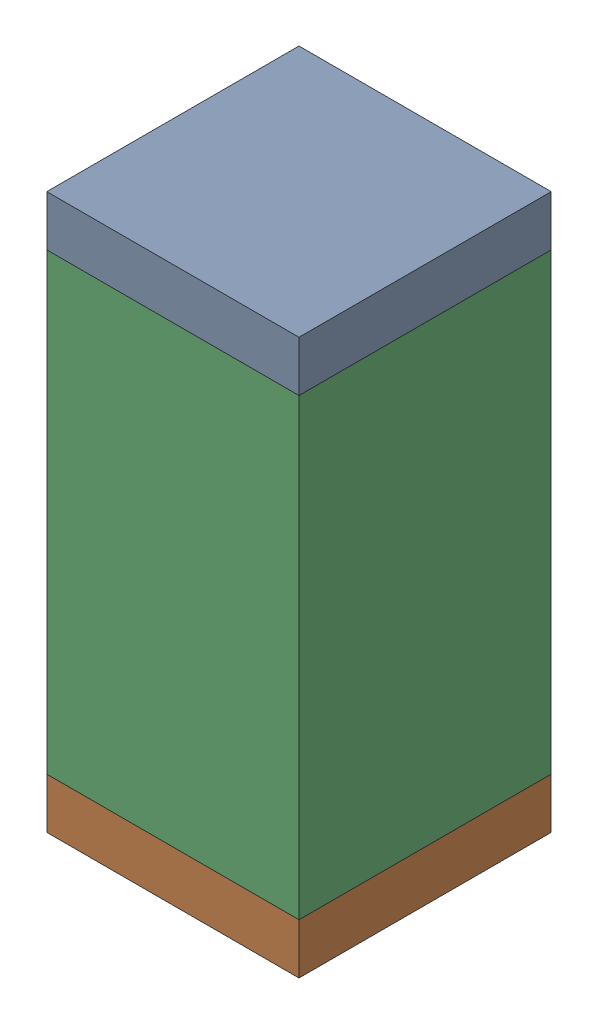
SolidWorks assembly C77, configuration Default. Lengths in mm.
Overall size (0.5 1.1 0.5).
6 component instances, 2 part files, 0 mates.
Components (placement in the parent):
- 810157360-1: 810157360 [Default] at (119.4 61.75 0) size (0.5 0.1 0.5)
  - Extruded_9-1: Extruded_9 [Default] at origin size (0.5 0.1 0.5)
- 810157360-2: 810157360 [Default] at (119.4 60.75 0) size (0.5 0.1 0.5)
  - Extruded_9-1: Extruded_9 [Default] at origin size (0.5 0.1 0.5)
- 791586336-1: 791586336 [Default] at (119.4 61.25 0) size (0.5 0.9 0.5)
  - Extruded_8-1: Extruded_8 [Default] at origin size (0.5 0.9 0.5)
